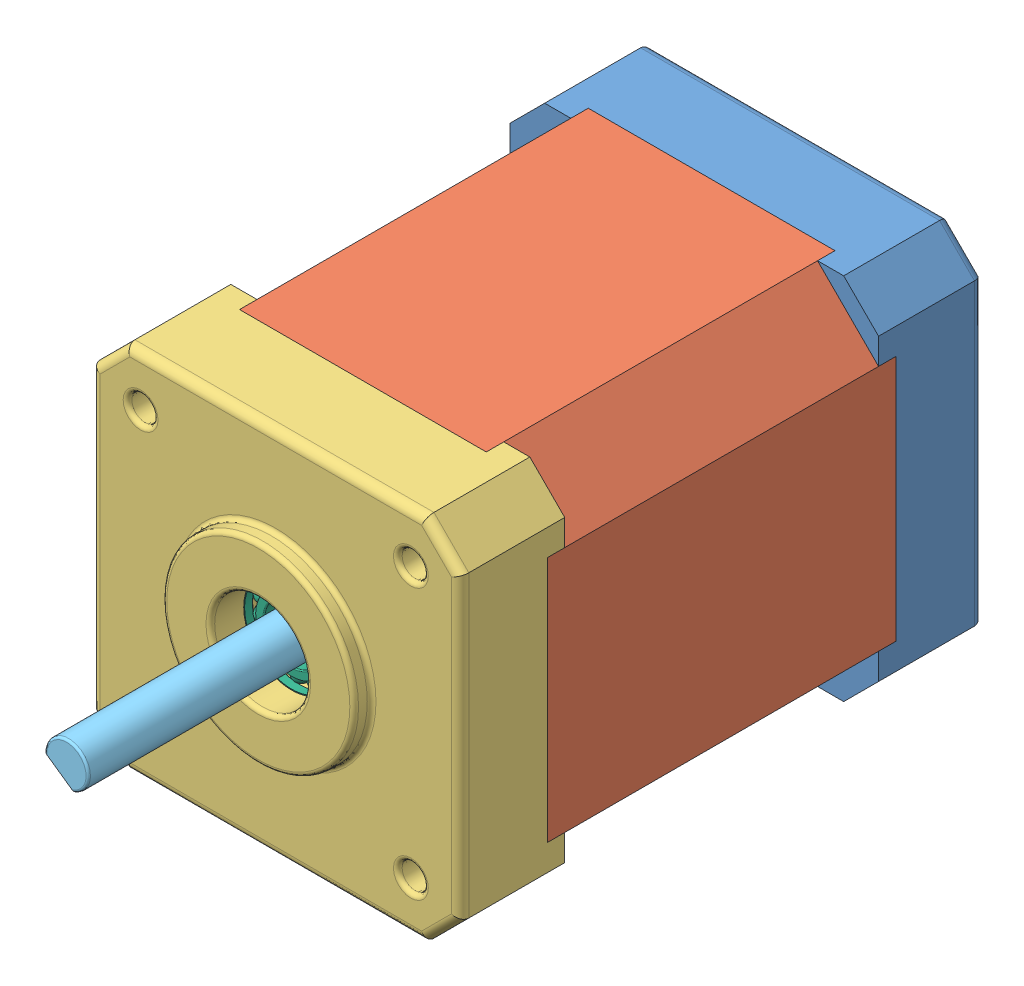
SolidWorks assembly NEMA_17_60mm_1.5A, configuration Default. Lengths in mm.
Overall size (42.3 42.3 84.16).
10 component instances, 6 part files, 0 mates.
Components (placement in the parent):
- Base-1: Base [Default] at (-10.3955 4.6172 0) size (42.3 42.3 12)
- Body_60mm-1: Body_60mm [Default] at (-10.3955 4.6172 10) size (42.3 42.3 40)
- FaceCap-1: FaceCap [Default] at (-10.3955 4.6172 60) x (-1 0 0) z (0 0 -1) size (42.3 42.3 14)
- 3mmX50mm_Sockethead(McMaster_91290A137)-1: 3mmX50mm_Sockethead(McMaster_91290A137) [91290A137] at (-25.8955 -10.8828 53) x (-0.535522 -0.844521 0) z (0 0 1) size (5.5 5.5 53.26)
- 3mmX50mm_Sockethead(McMaster_91290A137)-2: 3mmX50mm_Sockethead(McMaster_91290A137) [91290A137] at (5.1045 20.1172 53) x (-0.078076 -0.996947 0) z (0 0 1) size (5.5 5.5 53.26)
- 3mmX50mm_Sockethead(McMaster_91290A137)-3: 3mmX50mm_Sockethead(McMaster_91290A137) [91290A137] at (-25.8955 20.1172 53) x (0.373638 -0.927575 0) z (0 0 1) size (5.5 5.5 53.26)
- 3mmX50mm_Sockethead(McMaster_91290A137)-4: 3mmX50mm_Sockethead(McMaster_91290A137) [91290A137] at (5.1045 -10.8828 53) x (-0.438078 -0.898937 0) z (0 0 1) size (5.5 5.5 53.26)
- Shaft_60mm-1: Shaft_60mm [Default] at (-10.3955 4.6172 0) x (0.574856 0.818255 0) z (0 0 1) size (5 5 84.02)
- instrument ball bearing_68_am(PreviewCfg)-1: instrument ball bearing_68_am(PreviewCfg) [Default] at (-10.3955 4.6172 56.5875) x (0 0 -1) z (0.994238 0.107199 0) size (3.17 12.7 12.7)
- instrument ball bearing_68_am(PreviewCfg)-2: instrument ball bearing_68_am(PreviewCfg) [Default] at (-10.3955 4.6172 3.4125) x (0 0 1) z (-0.739703 -0.672934 0) size (3.17 12.7 12.7)
